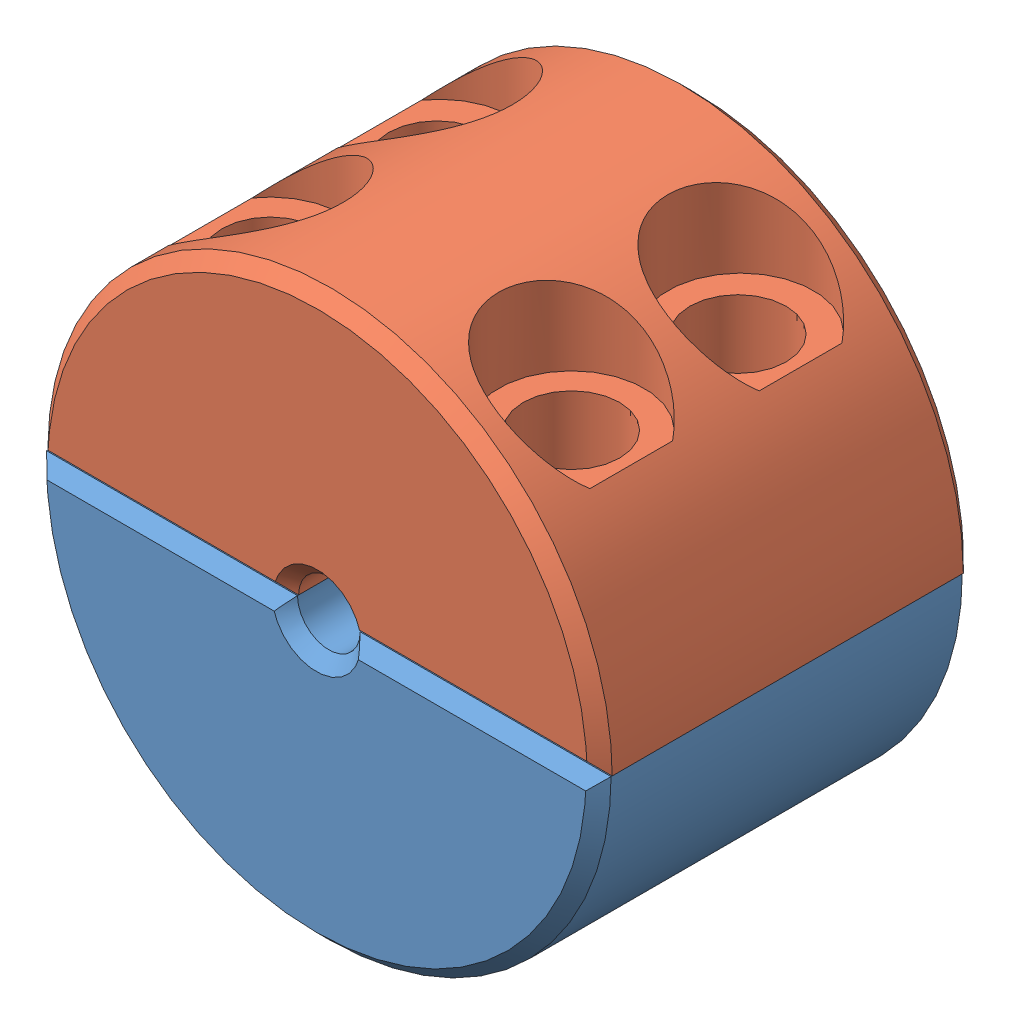
SolidWorks assembly CouplingAssembly, configuration Default. Lengths in mm.
Overall size (24.14 22.86 15.35).
2 component instances, 2 part files, 2 mates.
Components (placement in the parent):
- BottomHalfCoupling-1: BottomHalfCoupling [Default] at origin size (22.86 11.43 15.24)
- TopHalfCoupling-1: TopHalfCoupling [Default] at (0 0 -0.0451) size (24.14 11.43 15.35)
Mates (geometry in assembly coordinates):
- Concentric2: concentric: cylinder of BottomHalfCoupling-1 through (0 0 50.8) axis (0 0 -1) radius 12.7; cylinder of TopHalfCoupling-1 through (0 0 50.7549) axis (0 0 -1) radius 12.7
- Parallel6: parallel: plane of BottomHalfCoupling-1 through (-25.4 0 50.8) normal (0 1 0); plane of TopHalfCoupling-1 through (-25.4 0 50.7549) normal (0 -1 0)
